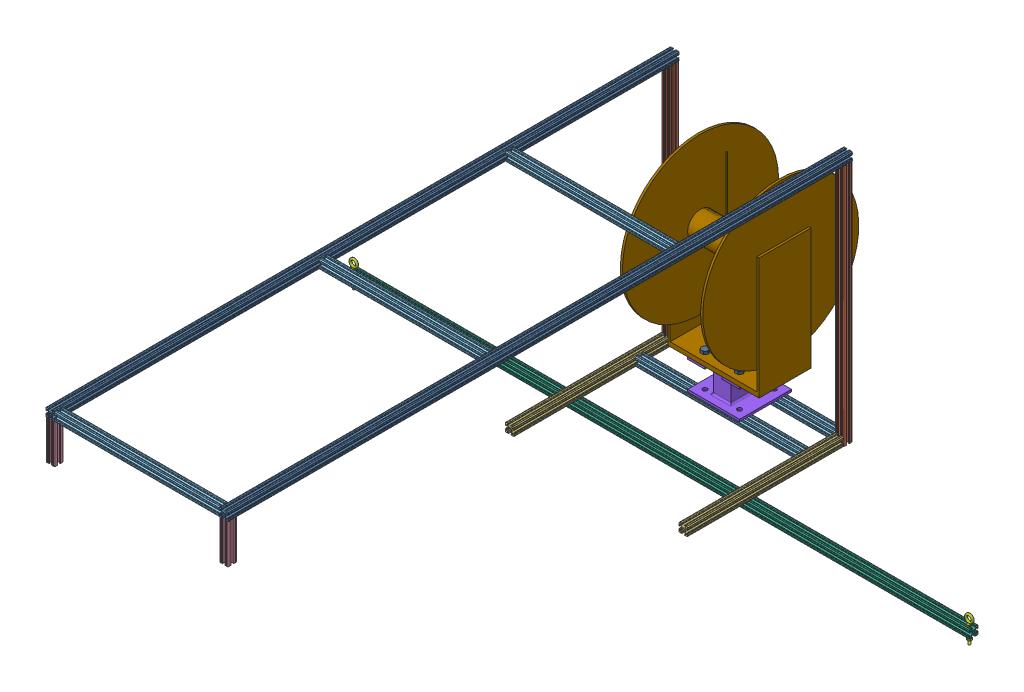
SolidWorks assembly _Retraction System Assy V1.0, configuration Default. Lengths in mm.
Overall size (1828.8 787.97 1993.9).
28 component instances, 11 part files, 3 mates.
Components (placement in the parent):
- Retraction Frame-1: Retraction Frame [Default] at (521.4621 224.8059 -60.9047) size (1828.8 787.97 1828.8)
  - 8020 -1inch - 5 ft 0 in-1: 8020 -1inch - 5 ft 0 in [47065T122] at (641.4215 936.2006 1437.8545) size (25.4 25.4 1828.8)
  - 8020 -1inch - 2 ft 4 inches-1: 8020 -1inch - 2 ft 4 inches [47065T122] at (641.4215 567.9006 536.1545) x (1 0 0) z (0 -1 0) size (25.4 25.4 711.2)
  - 8020 -1inch - 1 ft 6 in-1: 8020 -1inch - 1 ft 6 in [47065T122] at (641.4215 225.0006 777.4545) size (25.4 25.4 457.2)
  - 8020 -1inch - 0 ft 4.5 in-1: 8020 -1inch - 0 ft 4.5 in [47065T122] at (641.4215 866.3506 2339.5545) x (1 0 0) z (0 -1 0) size (25.4 25.4 114.3)
  - 8020 -1inch - 0 ft 4.5 in-2: 8020 -1inch - 0 ft 4.5 in [47065T122] at (133.4215 866.3506 2339.5545) x (1 0 0) z (0 -1 0) size (25.4 25.4 114.3)
  - 8020 -1inch - 1 ft 6 in-2: 8020 -1inch - 1 ft 6 in [47065T122] at (133.4215 225.0006 777.4545) size (25.4 25.4 457.2)
  - 8020 -1inch - 2 ft 4 inches-2: 8020 -1inch - 2 ft 4 inches [47065T122] at (133.4215 567.9006 536.1545) x (1 0 0) z (0 -1 0) size (25.4 25.4 711.2)
  - 8020 -1inch - 5 ft 0 in-2: 8020 -1inch - 5 ft 0 in [47065T122] at (133.4215 936.2006 1437.8545) size (25.4 25.4 1828.8)
  - 8020 -1inch - 1 ft 7 in-2: 8020 -1inch - 1 ft 7 in [47065T122] at (387.4215 225.0006 536.1545) x (0 0 1) z (-1 0 0) size (25.4 25.4 482.6)
  - 8020 -1inch - 1 ft 7 in-3: 8020 -1inch - 1 ft 7 in [47065T122] at (387.4215 225.0006 637.7545) x (0 0 1) z (-1 0 0) size (25.4 25.4 482.6)
  - 8020 -1inch - 1 ft 7 in-4: 8020 -1inch - 1 ft 7 in [47065T122] at (387.4215 936.2006 1018.7545) x (0 0 1) z (-1 0 0) size (25.4 25.4 482.6)
  - 8020 -1inch - 1 ft 7 in-5: 8020 -1inch - 1 ft 7 in [47065T122] at (387.4215 936.2006 2339.5545) x (0 0 1) z (-1 0 0) size (25.4 25.4 482.6)
  - 8020 -1inch - 1 ft 7 in-6: 8020 -1inch - 1 ft 7 in [47065T122] at (387.4215 936.2006 1564.8545) x (0 0 1) z (-1 0 0) size (25.4 25.4 482.6)
  - 8020 -1inch - 6 feet with guide line holes-1: 8020 -1inch - 6 feet with guide line holes [47065T122] at (387.4215 199.6006 815.5545) x (0 0 -1) z (1 0 0) size (25.4 25.4 1828.8)
  - 1.5 inch lifting eye-1: 1.5 inch lifting eye [3032T41] at (1289.1215 228.1756 815.5545) size (25.4 79.95 12.83)
  - 1.5 inch lifting eye-2: 1.5 inch lifting eye [3032T41] at (-514.2785 228.1756 815.5545) size (25.4 79.95 12.83)
- Retraction Reel Subassembly-1: Retraction Reel Subassembly [Default] at (971.1622 404.1291 429.8755) x (-1 0 0) z (0 1 0) size (266.7 457.2 628.3)
  - Retraction Bracket-1: Retraction Bracket [Default] at (-13.9214 19.9743 58.3774) size (152.4 152.4 88.9)
  - Retraction Reel-1: Retraction Reel [Default] at (-58.3714 96.1743 426.6774) size (266.7 457.2 539.4)
  - 1-2 inch x 1 inch SS, 1-2-20-1: 1-2 inch x 1 inch SS, 1-2-20 [92240A432] at (113.0786 146.9743 151.2462) x (0 0 -1) z (0.866025 0.5 0) size (33.84 22 19.05)
  - 1-2-20 SS Nut-1: 1-2-20 SS Nut [93839A825] at (113.0786 146.9743 136.9587) x (1 0 0) z (0 -1 0) size (19.05 8.94 22)
  - 1-2 inch x 1 inch SS, 1-2-20-2: 1-2 inch x 1 inch SS, 1-2-20 [92240A432] at (113.0786 45.3743 151.2462) x (0 0 -1) z (0 1 0) size (33.84 22 19.05)
  - 1-2 inch x 1 inch SS, 1-2-20-3: 1-2 inch x 1 inch SS, 1-2-20 [92240A432] at (11.4786 146.9743 151.2462) x (0 0 -1) z (0.866025 0.5 0) size (33.84 22 19.05)
  - 1-2 inch x 1 inch SS, 1-2-20-4: 1-2 inch x 1 inch SS, 1-2-20 [92240A432] at (11.4786 45.3743 151.2462) x (0 0 -1) z (0.866025 0.5 0) size (33.84 22 19.05)
  - 1-2-20 SS Nut-2: 1-2-20 SS Nut [93839A825] at (11.4786 146.9743 136.9587) x (0.866025 0.5 0) z (0.5 -0.866025 0) size (19.05 8.94 22)
  - 1-2-20 SS Nut-3: 1-2-20 SS Nut [93839A825] at (11.4786 45.3743 136.9587) x (0.866025 0.5 0) z (0.5 -0.866025 0) size (19.05 8.94 22)
  - 1-2-20 SS Nut-4: 1-2-20 SS Nut [93839A825] at (113.0786 45.3743 136.9587) x (0.866025 -0.5 0) z (-0.5 -0.866025 0) size (19.05 8.94 22)
Mates (geometry in assembly coordinates):
- Coincident1: coincident anti-aligned: plane of Retraction Frame-1/8020 -1inch - 1 ft 7 in-2 through (667.5836 462.5065 468.9167) normal (0 1 0); plane of Retraction Reel Subassembly-1/Retraction Bracket-1 through (985.0836 462.5065 449.8499) normal (0 -1 0)
- Distance1: distance = 165.1 mm anti-aligned: plane of Retraction Reel Subassembly-1/Retraction Bracket-1 through (985.0836 468.8565 449.8499) normal (1 0 0); plane of Retraction Frame-1/8020 -1inch - 2 ft 4 inches-1 through (1150.1836 437.1065 468.9168) normal (-1 0 0)
- Distance2: distance = 12.7 mm aligned: plane of Retraction Reel Subassembly-1/Retraction Bracket-1 through (985.0836 468.8565 449.8499) normal (0 0 -1); plane of Retraction Frame-1/8020 -1inch - 1 ft 7 in-2 through (667.5836 459.3569 462.5499) normal (0 0 -1)
